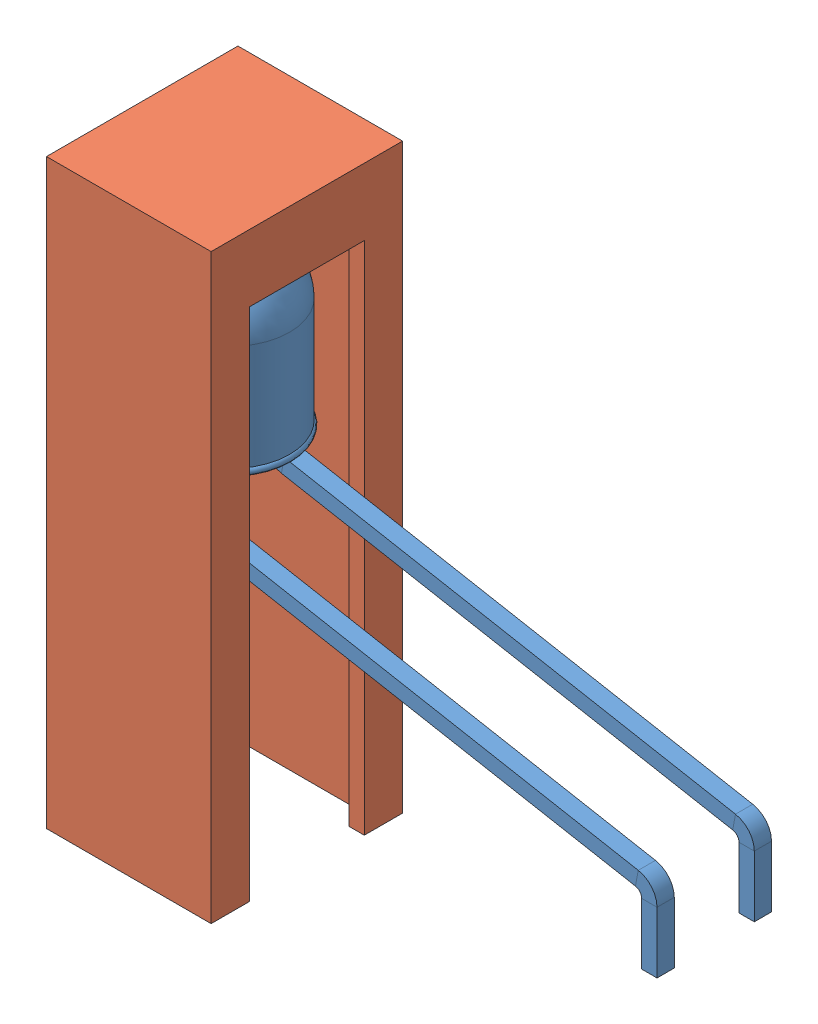
SolidWorks assembly sparkfunIR_LEDandCase, configuration 2Pin. Lengths in mm.
Overall size (14.94 15.2 5).
2 component instances, 2 part files, 4 mates.
Components (placement in the parent):
- sparkfunIR_LED-1: sparkfunIR_LED [2Pin] at (-40.5025 -12.0786 32.4491)
- sparkfunIR_casing-1: sparkfunIR_casing [Default] at (-40.6525 -5.8286 32.4491) x (1 0 0) z (0 0 -1)
Mates (geometry in assembly coordinates):
- Tangent1: tangent anti-aligned: sphere of sparkfunIR_LED-1; plane of sparkfunIR_casing-1 through (-40.6525 -7.5786 32.4491) normal (0 -1 0)
- Parallel2: parallel aligned: plane of sparkfunIR_LED-1 through (-40.5025 -12.0786 32.4491) normal (0 -1 0); plane of sparkfunIR_casing-1 through (-42.8025 -21.0286 29.9491) normal (0 -1 0)
- Coincident3: coincident anti-aligned: plane of sparkfunIR_LED-1 through (-40.5025 -12.0786 32.4491) normal (0 0 1); plane of sparkfunIR_casing-1 through (-40.6525 -5.8286 32.4491) normal (0 0 -1)
- Coincident4: coincident: point of sparkfunIR_LED-1; moEndPointRef_w of sparkfunIR_casing-1
